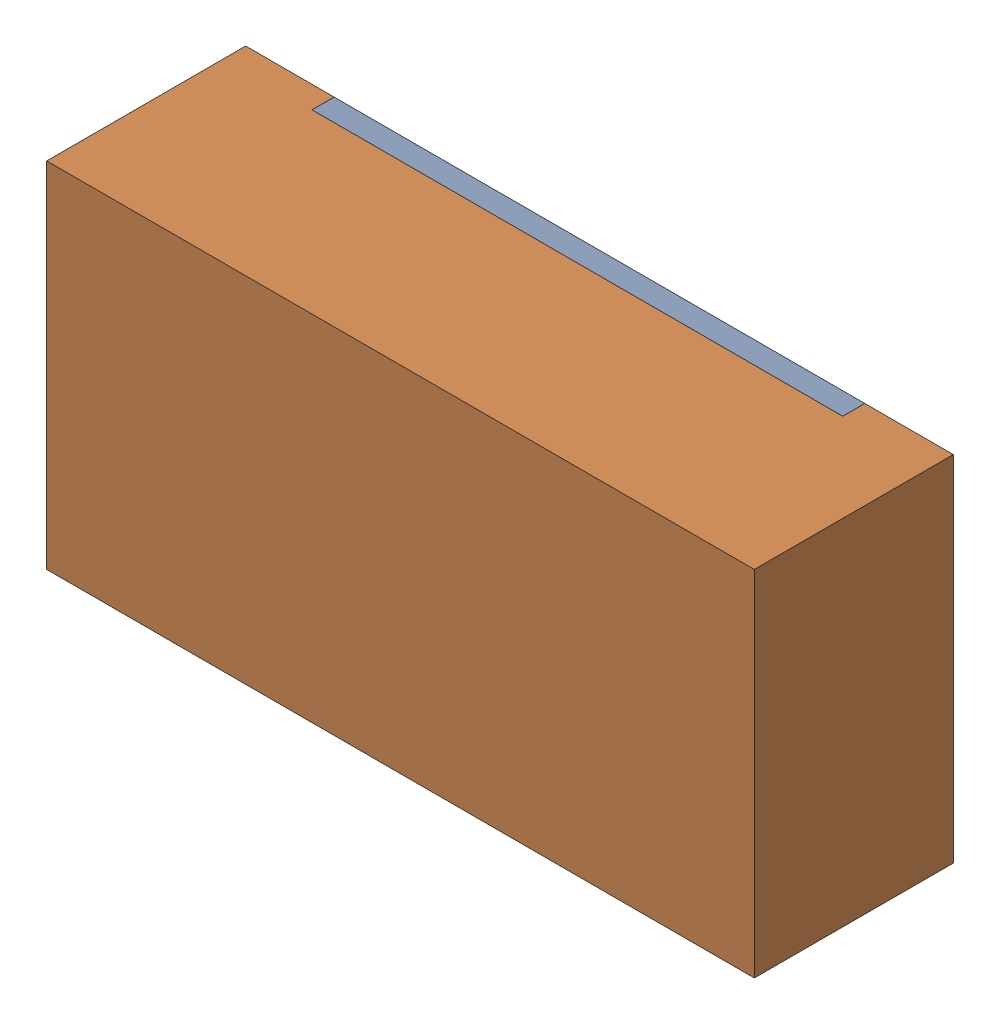
SolidWorks assembly R8, configuration 默认. Lengths in mm.
Overall size (1.6 0.8 0.45).
3 component instances, 2 part files, 0 mates.
Components (placement in the parent):
- R8-subassembly-1-1: R8-subassembly-1 [默认] at (3.6831 17.3989 -1.6914) x (1 0 0) z (0 0 -1) size (1.6 0.8 0.45)
  - R0603-1: R0603 [默认] at origin size (1.2 0.8 0.05)
  - R0603-1-1: R0603-1 [默认] at origin size (1.6 0.8 0.45)
